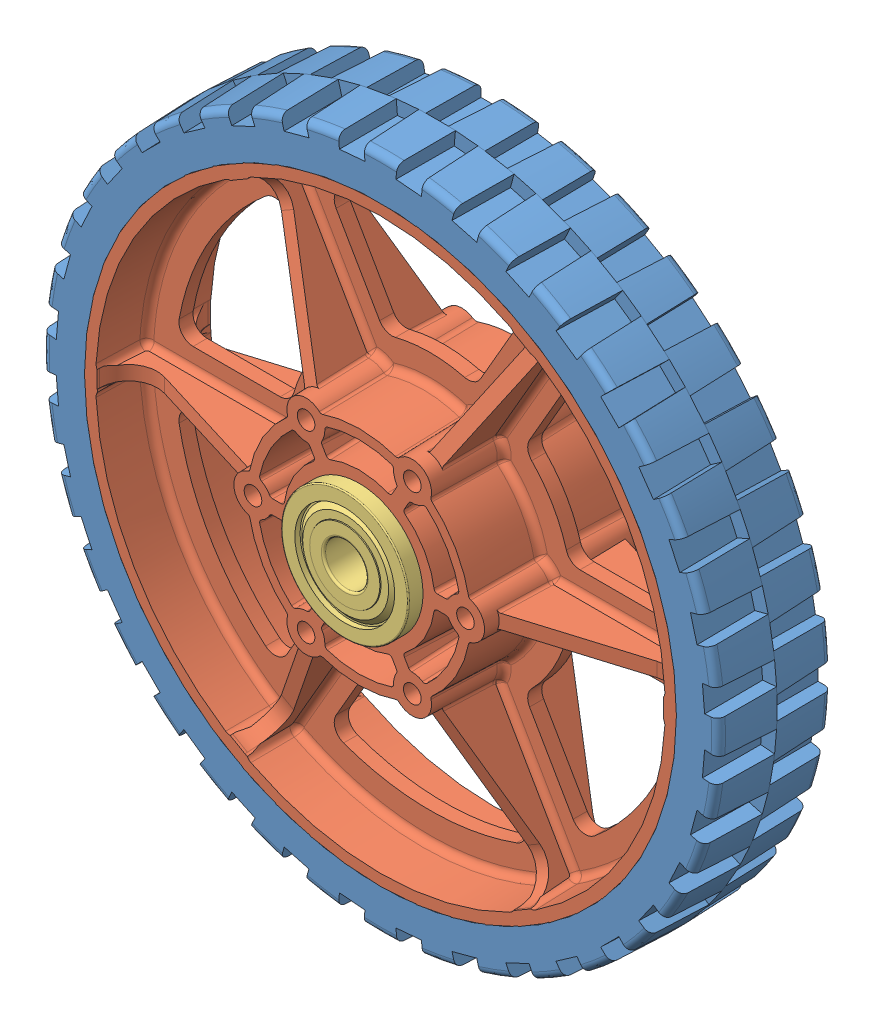
SolidWorks assembly HiGripWheel AndyMark am-0940, configuration Default. Lengths in mm.
Overall size (152.4 152.4 41.4).
4 component instances, 3 part files, 0 mates.
Components (placement in the parent):
- 6 HiGrip Tread-1: 6 HiGrip Tread [Default] at (-18.8802 3.0972 -4.839) size (152.4 152.4 25.58)
- 6in 2008 FIRST Hub-1: 6in 2008 FIRST Hub [Default] at (-18.8802 3.0972 -4.839) size (139.7 139.7 35.48)
- DBK_1614ZZBearing_am-0209-1: DBK_1614ZZBearing_am-0209 [Default] at (-18.8802 3.0972 -8.0719) x (0 0 1) z (1 0 0) size (9.53 28.58 28.58)
- DBK_1614ZZBearing_am-0209-2: DBK_1614ZZBearing_am-0209 [Default] at (-18.8802 3.0972 23.7947) x (0 0 -1) z (1 0 0) size (9.53 28.58 28.58)
